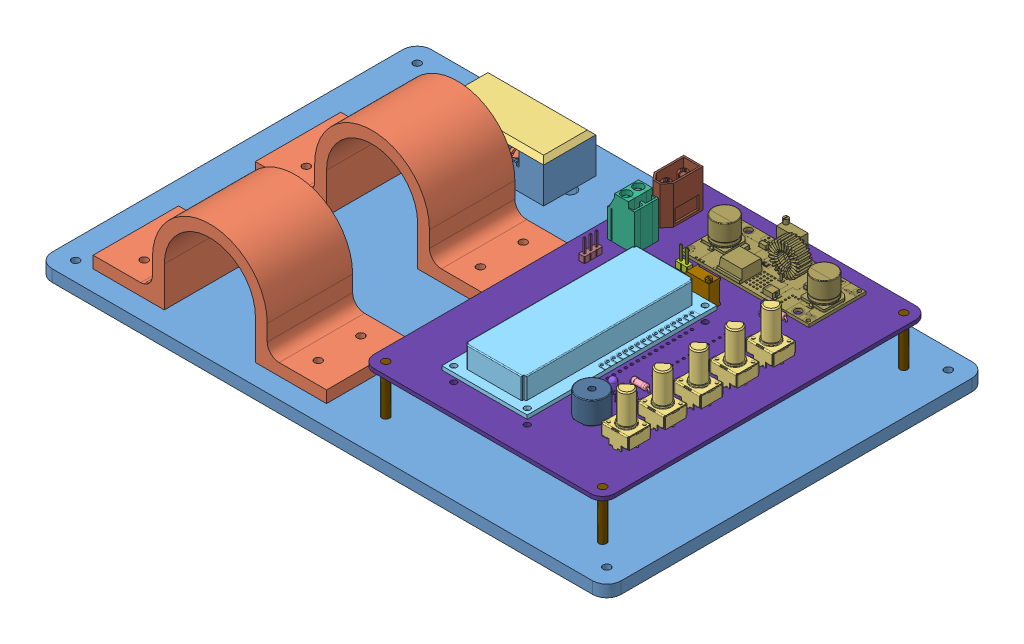
SolidWorks assembly Kendali Motor DC, configuration Default. Lengths in mm.
Overall size (240 46 160).
62 component instances, 21 part files, 17 mates.
Components (placement in the parent):
- Alas untuk Motor DC-1: Alas untuk Motor DC [Default] at (102.4744 125.7327 229.8519) size (240 5 160)
- Holder Motor DC-1: Holder Motor DC [Default] at (46.4744 147.5327 232.8519) size (98.4 41 36)
- Holder Motor DC-2: Holder Motor DC [Default] at (46.4744 147.5327 301.2519) size (98.4 41 36)
- SPEED CONTROL MOTOR DC-1: SPEED CONTROL MOTOR DC [Default] at (234.6744 149.1327 130.7919) x (0 0 1) z (0 1 0) size (137.16 101.6 38.13)
  - R-0904N-L-20F-green-1: R-0904N-L-20F-green [Default] at (141.184 -41.768 1.65) x (-1 0 0) z (0 0 1) size (11.32 12.6 23.8)
    - COMPOUND-1: COMPOUND [Default] at origin size (11.32 12.6 23.8)
  - R_Axial_DIN0207_L6.3mm_D2.5mm_P7.62mm_Horizontal-1: R_Axial_DIN0207_L6.3mm_D2.5mm_P7.62mm_Horizontal [Default] at (63.5 -52.07 1.65) x (0 -1 0) z (0 0 1) size (8.22 2.5 5.5)
    - SOLID-1: SOLID [Default] at origin size (8.22 2.5 5.5)
  - R_Axial_DIN0207_L6.3mm_D2.5mm_P7.62mm_Horizontal-2: R_Axial_DIN0207_L6.3mm_D2.5mm_P7.62mm_Horizontal [Default] at (118.364 -55.118 1.65) x (0 -1 0) z (0 0 1) size (8.22 2.5 5.5)
    - SOLID-1: SOLID [Default] at origin size (8.22 2.5 5.5)
  - WC1602A-1: WC1602A [Default] at (86.364 -68.9705 1.65) size (80 36 15)
    - SOLID_2-1: SOLID_2 [Default] at origin size (80 36 15)
  - 691236510002 (rev1)-1: 691236510002 (rev1) [Default] at (61 -119.8 1.65) x (0 1 0) z (1 0 0) size (11.35 22 10.76)
    - COMPOUND_2-1: COMPOUND_2 [Default] at origin size (11.35 22 10.76)
  - PinHeader_1x02_P2.54mm_Vertical-1: PinHeader_1x02_P2.54mm_Vertical [Default] at (66.04 -91.44 1.65) size (2.54 5.08 11.54)
    - SOLID_3-1: SOLID_3 [Default] at origin size (2.54 5.08 11.54)
  - LED_D3.0mm-1: LED_D3.0mm [Default] at (68.58 -54.61 1.65) x (0 -1 0) z (0 0 1) size (3.4 3.8 10.8)
    - SOLID_4-1: SOLID_4 [Default] at origin size (3.4 3.8 10.8)
  - Potentiometer_Bourns_3296W_Vertical-1: Potentiometer_Bourns_3296W_Vertical [Default] at (73.914 -74.168 1.65) x (0 1 0) z (0 0 1) size (9.53 4.83 17.07)
    - SOLID_5-1: SOLID_5 [Default] at origin size (9.53 4.83 17.07)
  - MagneticBuzzer_ProSignal_ABI-009-RC-1: MagneticBuzzer_ProSignal_ABI-009-RC [Default] at (138.684 -62.728 1.65) x (0 1 0) z (0 0 1) size (12 12 12.53)
    - SOLID_6-1: SOLID_6 [Default] at origin size (12 12 12.53)
  - AMASS_XT60-M_1x02_P7.2mm_Vertical-1: AMASS_XT60-M_1x02_P7.2mm_Vertical [Default] at (51.86 -114.3 1.65) x (-1 0 0) z (0 0 1) size (15.9 8.1 20.5)
    - COMPOUND_3-1: COMPOUND_3 [Default] at origin size (15.9 8.1 20.5)
  - R-0904N-L-20F-green-2: R-0904N-L-20F-green [Default] at (95.464 -41.768 1.65) x (-1 0 0) z (0 0 1) size (11.32 12.6 23.8)
    - COMPOUND-1: COMPOUND [Default] at origin size (11.32 12.6 23.8)
  - R_Axial_DIN0207_L6.3mm_D2.5mm_P7.62mm_Horizontal-3: R_Axial_DIN0207_L6.3mm_D2.5mm_P7.62mm_Horizontal [Default] at (123.444 -55.118 1.65) x (0 -1 0) z (0 0 1) size (8.22 2.5 5.5)
    - SOLID-1: SOLID [Default] at origin size (8.22 2.5 5.5)
  - R-0904N-L-20F-green-3: R-0904N-L-20F-green [Default] at (125.944 -41.768 1.65) x (-1 0 0) z (0 0 1) size (11.32 12.6 23.8)
    - COMPOUND-1: COMPOUND [Default] at origin size (11.32 12.6 23.8)
  - R-0904N-L-20F-green-4: R-0904N-L-20F-green [Default] at (80.184 -41.768 1.65) x (-1 0 0) z (0 0 1) size (11.32 12.6 23.8)
    - COMPOUND-1: COMPOUND [Default] at origin size (11.32 12.6 23.8)
  - LED_D3.0mm-2: LED_D3.0mm [Default] at (128.524 -58.928 1.65) x (0 -1 0) z (0 0 1) size (3.4 3.8 10.8)
    - SOLID_4-1: SOLID_4 [Default] at origin size (3.4 3.8 10.8)
  - XL4015_MODELO_PISTAS-1: XL4015_MODELO_PISTAS [Default] at (48.26 -71.12 -52.35) x (0 1 0) z (0 0 1) size (54.01 24.02 14.75)
    - COMPOUND_4-1: COMPOUND_4 [Default] at origin size (54.01 24.02 14.75)
  - R-0904N-L-20F-green-5: R-0904N-L-20F-green [Default] at (110.704 -41.768 1.65) x (-1 0 0) z (0 0 1) size (11.32 12.6 23.8)
    - COMPOUND-1: COMPOUND [Default] at origin size (11.32 12.6 23.8)
  - PinHeader_1x03_P2.54mm_Vertical-1: PinHeader_1x03_P2.54mm_Vertical [Default] at (78.755 -116.84 1.65) x (0 1 0) z (0 0 1) size (2.54 7.62 11.54)
    - SOLID_7-1: SOLID_7 [Default] at origin size (2.54 7.62 11.54)
  - D_SMB-1: D_SMB [Default] at (53.34 -38.1 -0.05) x (1 0 0) z (0 0 -1) size (5.3 3.55 2.15)
    - SOLID_8-1: SOLID_8 [Default] at origin size (5.3 3.55 2.15)
  - SOIC-8_3.9x4.9mm_P1.27mm-1: SOIC-8_3.9x4.9mm_P1.27mm [Default] at (66.04 -101.6 -0.05) x (0 1 0) z (0 0 -1) size (6 4.9 1.75)
    - SOLID_9-1: SOLID_9 [Default] at origin size (6 4.9 1.75)
  - arduino1-1: arduino1 [Default] at (98.879 -84.698 -12.55) x (1 0 0) z (0 -1 0) size (75.6 16.19 53.3)
    - COMPOUND_5-1: COMPOUND_5 [Default] at origin size (75.6 16.19 53.3)
  - D_SMB-2: D_SMB [Default] at (53.34 -104.14 -0.05) x (-1 0 0) z (0 0 -1) size (5.3 3.55 2.15)
    - SOLID_8-1: SOLID_8 [Default] at origin size (5.3 3.55 2.15)
  - _autosave-SPEED_CONTROL PCB-1: _autosave-SPEED_CONTROL PCB [Default] at origin size (137.16 101.6 1.6)
- Spacer-1: Spacer [Default] at (204.1944 150.7327 293.3519) x (1 0 0) z (0 -1 0) size (3.2 3.2 25)
- Spacer-2: Spacer [Default] at (204.1944 150.7327 166.3519) x (1 0 0) z (0 -1 0) size (3.2 3.2 25)
- Spacer-3: Spacer [Default] at (112.7544 150.7327 293.3519) x (1 0 0) z (0 -1 0) size (3.2 3.2 25)
- Spacer-4: Spacer [Default] at (112.7544 150.7327 166.3519) x (1 0 0) z (0 -1 0) size (3.2 3.2 25)
- Terminal block TB-1503-2: Terminal block TB-1503 [Default] at (61.9486 166.8027 192.9878) size (45.5 16.8 22)
  - _X2_0414043504420430043B044C_X0_1-1: _X2_0414043504420430043B044C_X0_1 [Default] at (-15.378 -36.07 -20.6359) x (1 0 0) z (0 1 0) size (45.5 22 15)
  - _X2_04120438043D0442_X0_ A.M3-6gx3 _X2_0413041E04210422_X0_ 17473-80-1: _X2_04120438043D0442_X0_ A.M3-6gx3 _X2_0413041E04210422_X0_ 17473-80 [Default] at (-15.378 -25.17 -12.6359) size (5.54 5.1 5.53)
  - _X2_04120438043D0442_X0_ A.M3-6gx3 _X2_0413041E04210422_X0_ 17473-80-2: _X2_04120438043D0442_X0_ A.M3-6gx3 _X2_0413041E04210422_X0_ 17473-80 [Default] at (-6.5446 -25.17 -12.6359) size (5.54 5.1 5.53)
  - _X2_04120438043D0442_X0_ A.M3-6gx3 _X2_0413041E04210422_X0_ 17473-80-3: _X2_04120438043D0442_X0_ A.M3-6gx3 _X2_0413041E04210422_X0_ 17473-80 [Default] at (-15.378 -25.17 -28.6359) size (5.54 5.1 5.53)
  - _X2_04120438043D0442_X0_ A.M3-6gx3 _X2_0413041E04210422_X0_ 17473-80-4: _X2_04120438043D0442_X0_ A.M3-6gx3 _X2_0413041E04210422_X0_ 17473-80 [Default] at (-6.5446 -25.17 -28.6359) size (5.54 5.1 5.53)
  - _X2_04120438043D0442_X0_ A.M3-6gx3 _X2_0413041E04210422_X0_ 17473-80-5: _X2_04120438043D0442_X0_ A.M3-6gx3 _X2_0413041E04210422_X0_ 17473-80 [Default] at (-24.1631 -25.17 -28.6359) size (5.54 5.1 5.53)
  - _X2_04120438043D0442_X0_ A.M3-6gx3 _X2_0413041E04210422_X0_ 17473-80-6: _X2_04120438043D0442_X0_ A.M3-6gx3 _X2_0413041E04210422_X0_ 17473-80 [Default] at (-24.2113 -25.17 -12.6359) size (5.54 5.1 5.53)
  - _X2_0414043504420430043B044C_X0_2-1: _X2_0414043504420430043B044C_X0_2 [Default] at (-15.378 -21.07 -20.6359) x (0 0 1) z (-1 0 0) size (22 5.3 45.5)
Mates (geometry in assembly coordinates):
- Coincident9: coincident anti-aligned: plane of Alas untuk Motor DC-1 through (102.4744 130.7327 229.8519) normal (0 1 0); plane of Holder Motor DC-1 through (65.6744 130.7327 196.8519) normal (0 -1 0)
- Coincident10: coincident anti-aligned: plane of Alas untuk Motor DC-1 through (102.4744 130.7327 229.8519) normal (0 1 0); plane of Holder Motor DC-2 through (27.2744 130.7327 265.2519) normal (0 -1 0)
- Concentric14: concentric aligned: cylinder of Alas untuk Motor DC-1 through (112.7544 125.7327 166.3519) axis (0 1 0) radius 1.6; cylinder of Spacer-4 through (112.7544 125.7327 166.3519) axis (0 1 0) radius 1.6
- Concentric15: concentric aligned: cylinder of Alas untuk Motor DC-1 through (204.1944 125.7327 293.3519) axis (0 1 0) radius 1.6; cylinder of Spacer-1 through (204.1944 125.7327 293.3519) axis (0 1 0) radius 1.6
- Coincident11: coincident aligned: plane of Alas untuk Motor DC-1 through (102.4744 125.7327 229.8519) normal (0 -1 0); plane of Spacer-1 through (204.1944 125.7327 293.3519) normal (0 -1 0)
- Coincident12: coincident aligned: plane of Alas untuk Motor DC-1 through (102.4744 125.7327 229.8519) normal (0 -1 0); plane of Spacer-4 through (112.7544 125.7327 166.3519) normal (0 -1 0)
- Coincident14: coincident anti-aligned: plane of Alas untuk Motor DC-1 through (102.4744 130.7327 229.8519) normal (0 1 0); plane of Terminal block TB-1503-2/_X2_0414043504420430043B044C_X0_1-1 through (46.5706 130.7327 172.3519) normal (0 -1 0)
- Concentric30: concentric aligned: cylinder of Alas untuk Motor DC-1 through (9.7744 125.7327 205.8519) axis (0 1 0) radius 1.6; cylinder of Holder Motor DC-1 through (9.7744 130.7327 205.8519) axis (0 1 0) radius 1.6
- Concentric31: concentric aligned: cylinder of Alas untuk Motor DC-1 through (83.1744 125.7327 223.8519) axis (0 1 0) radius 1.6; cylinder of Holder Motor DC-1 through (83.1744 130.7327 223.8519) axis (0 1 0) radius 1.6
- Concentric32: concentric aligned: cylinder of Alas untuk Motor DC-1 through (9.7744 125.7327 274.2519) axis (0 1 0) radius 1.6; cylinder of Holder Motor DC-2 through (9.7744 130.7327 274.2519) axis (0 1 0) radius 1.6
- Tangent2: tangent anti-aligned: plane of Alas untuk Motor DC-1 through (23.9744 125.7327 174.4519) normal (0 0 -1); cylinder of Terminal block TB-1503-2/_X2_0414043504420430043B044C_X0_1-1 through (64.8206 138.2327 172.3519) axis (0 1 0) radius 2.1
- Concentric34: concentric aligned: cylinder of Alas untuk Motor DC-1 through (204.1944 125.7327 166.3519) axis (0 1 0) radius 1.6; cylinder of Spacer-2 through (204.1944 125.7327 166.3519) axis (0 1 0) radius 1.6
- Concentric35: concentric aligned: cylinder of Alas untuk Motor DC-1 through (112.7544 125.7327 293.3519) axis (0 1 0) radius 1.6; cylinder of Spacer-3 through (112.7544 125.7327 293.3519) axis (0 1 0) radius 1.6
- Concentric36: concentric aligned: cylinder of SPEED CONTROL MOTOR DC-1/_autosave-SPEED_CONTROL PCB-1 through (204.1944 148.3327 166.3519) axis (0 1 0) radius 1.6; cylinder of Spacer-2 through (204.1944 125.7327 166.3519) axis (0 1 0) radius 1.6
- Concentric37: concentric aligned: cylinder of SPEED CONTROL MOTOR DC-1/_autosave-SPEED_CONTROL PCB-1 through (112.7544 148.3327 293.3519) axis (0 1 0) radius 1.6; cylinder of Spacer-3 through (112.7544 125.7327 293.3519) axis (0 1 0) radius 1.6
- Coincident17: coincident aligned: plane of SPEED CONTROL MOTOR DC-1/_autosave-SPEED_CONTROL PCB-1 through (158.4744 150.7327 229.8519) normal (0 1 0); plane of Spacer-1 through (204.1944 150.7327 293.3519) normal (0 1 0)
- Tangent4: tangent anti-aligned: plane of Alas untuk Motor DC-1 through (23.9744 125.7327 174.4519) normal (0 0 -1); cylinder of Terminal block TB-1503-2/_X2_0414043504420430043B044C_X0_1-1 through (28.3206 138.2327 172.3519) axis (0 1 0) radius 2.1
